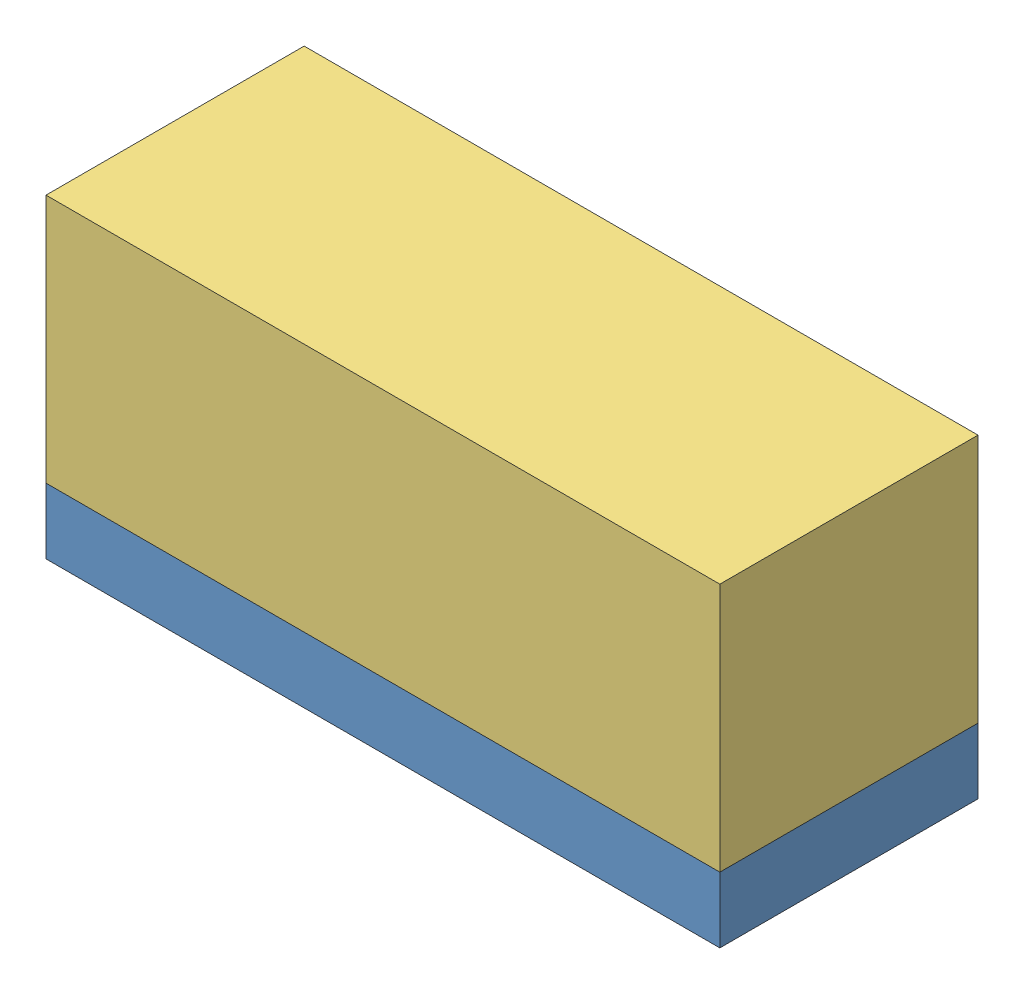
SolidWorks assembly verpakking, configuration Default. Lengths in mm.
Overall size (308 144 118).
3 component instances, 3 part files, 6 mates.
Components (placement in the parent):
- onderkant verpakking-1: onderkant verpakking [Default] at origin size (308 60 118)
- deksel doos verpakking-1: deksel doos verpakking [Default] at (0 26 0) size (278 54 88)
- plexiglazen bovenkant-1: plexiglazen bovenkant [Default] at (0 110 0) x (-1 0 0) z (0 0 1) size (308 114 118)
Mates (geometry in assembly coordinates):
- Coincident1: coincident: plane of onderkant verpakking-1 through (0 26 0) normal (0 1 0); plane of deksel doos verpakking-1 through (0 26 0) normal (0 -1 0)
- Distance1: distance = 1 mm: plane of deksel doos verpakking-1 through (-139 30 44) normal (0 0 1); plane of onderkant verpakking-1 through (140 -20 45) normal (0 0 -1)
- Distance2: distance = 1 mm: plane of deksel doos verpakking-1 through (139 30 44) normal (1 0 0); plane of onderkant verpakking-1 through (140 -20 45) normal (-1 0 0)
- Coincident15: coincident: plane of onderkant verpakking-1 through (0 0 0) normal (0 1 0); plane of plexiglazen bovenkant-1 through (-150 0 55) normal (0 -1 0)
- Coincident16: coincident: line of onderkant verpakking-1 through (154 0 59) axis (-1 0 0); line of plexiglazen bovenkant-1 through (-154 0 59) axis (1 0 0)
- Coincident17: coincident: line of onderkant verpakking-1 through (154 0 -59) axis (0 0 1); line of plexiglazen bovenkant-1 through (154 0 59) axis (0 0 -1)
